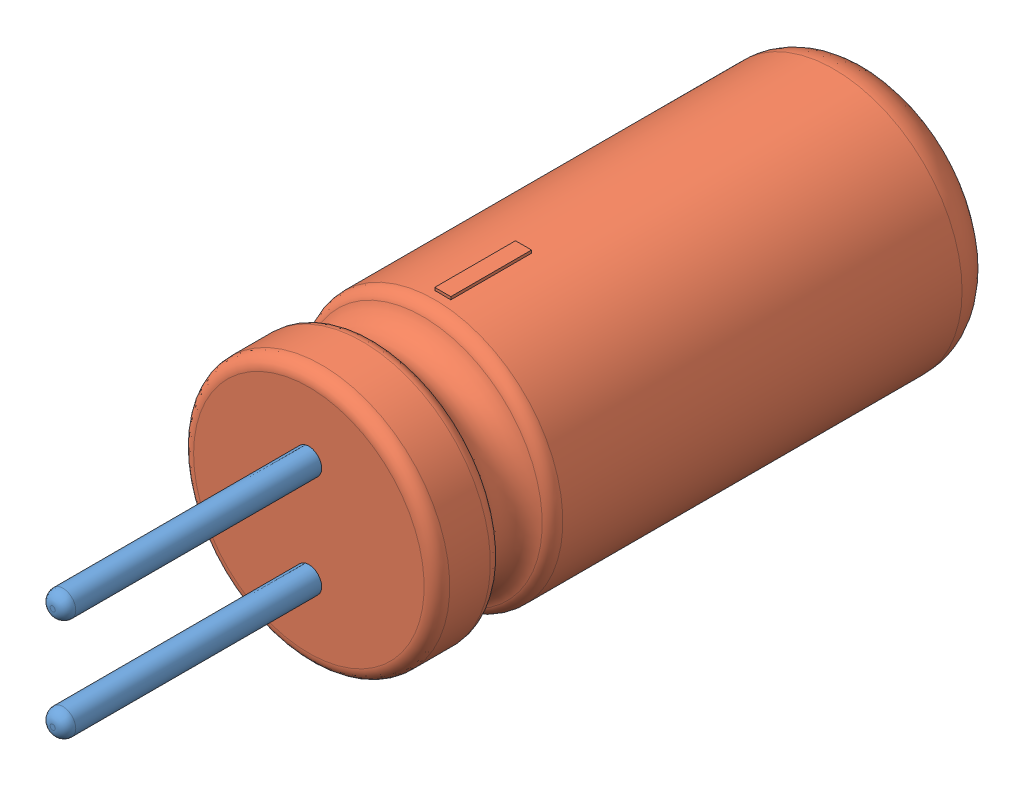
SolidWorks assembly User Library-C3-5-11-V, configuration Default. Lengths in mm.
Overall size (5 5.05 16).
3 component instances, 2 part files, 0 mates.
Components (placement in the parent):
- User Library-C3-5-11-V_pata-0.5-5V-1: User Library-C3-5-11-V_pata-0.5-5V [Default] at (0 -1 5) x (1 0 0) z (0 1 0) size (0.5 5 0.5)
- User Library-C3-5-11-V_pata-0.5-5V-2: User Library-C3-5-11-V_pata-0.5-5V [Default] at (0 1 5) x (1 0 0) z (0 1 0) size (0.5 5 0.5)
- User Library-C3-5-11-V_C3-5-11-1: User Library-C3-5-11-V_C3-5-11 [Default] at origin size (5 5.05 11)
